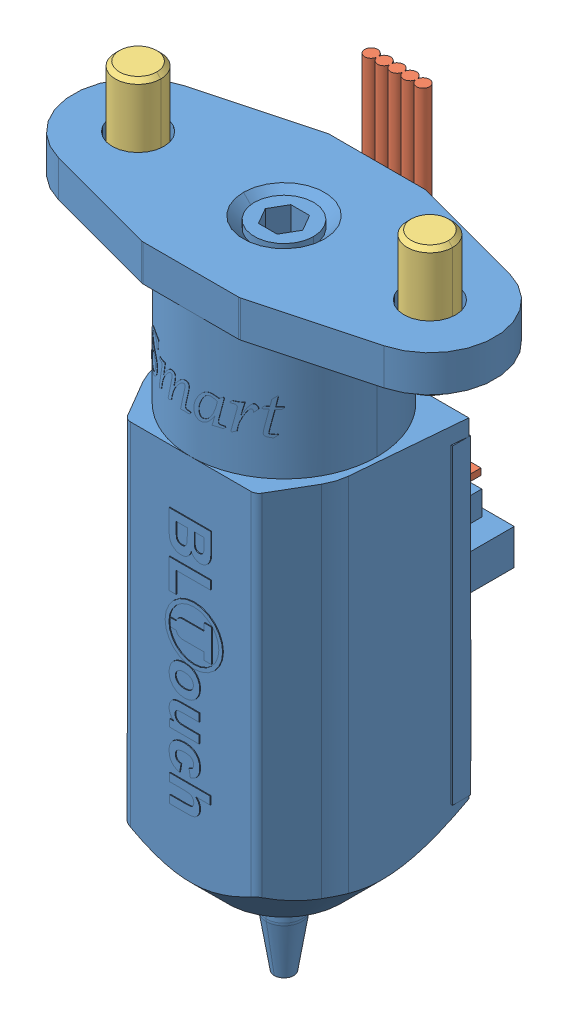
SolidWorks assembly bltouch_v3-1_asm, configuration Default. Lengths in mm.
Overall size (26 44.7 14.33).
5 component instances, 3 part files, 0 mates.
Components (placement in the parent):
- bltouch_v3-1_asm.stp-1: bltouch_v3-1_asm.stp [Default] at origin size (26 44.7 14.33)
  - BLTOUCH_V3-1.stp-1: BLTOUCH_V3-1.stp [Default] at (0 40.3 0) x (-1 0 0) z (0 0 -1) size (26 40.3 14.33)
  - BLTOUCH_V3-1_CABLE.stp-1: BLTOUCH_V3-1_CABLE.stp [Default] at (0 24.3 -6.7) x (-1 0 0) z (0 0 -1) size (7.9 23.9 3)
  - BLTOUCH_V3-1_SCREW.stp-1: BLTOUCH_V3-1_SCREW.stp [Default] at (9 38.05 0) x (1 0 0) z (0 0 -1) size (5.5 7.75 5.5)
  - BLTOUCH_V3-1_SCREW.stp-2: BLTOUCH_V3-1_SCREW.stp [Default] at (-9 38.05 0) x (1 0 0) z (0 0 -1) size (5.5 7.75 5.5)
